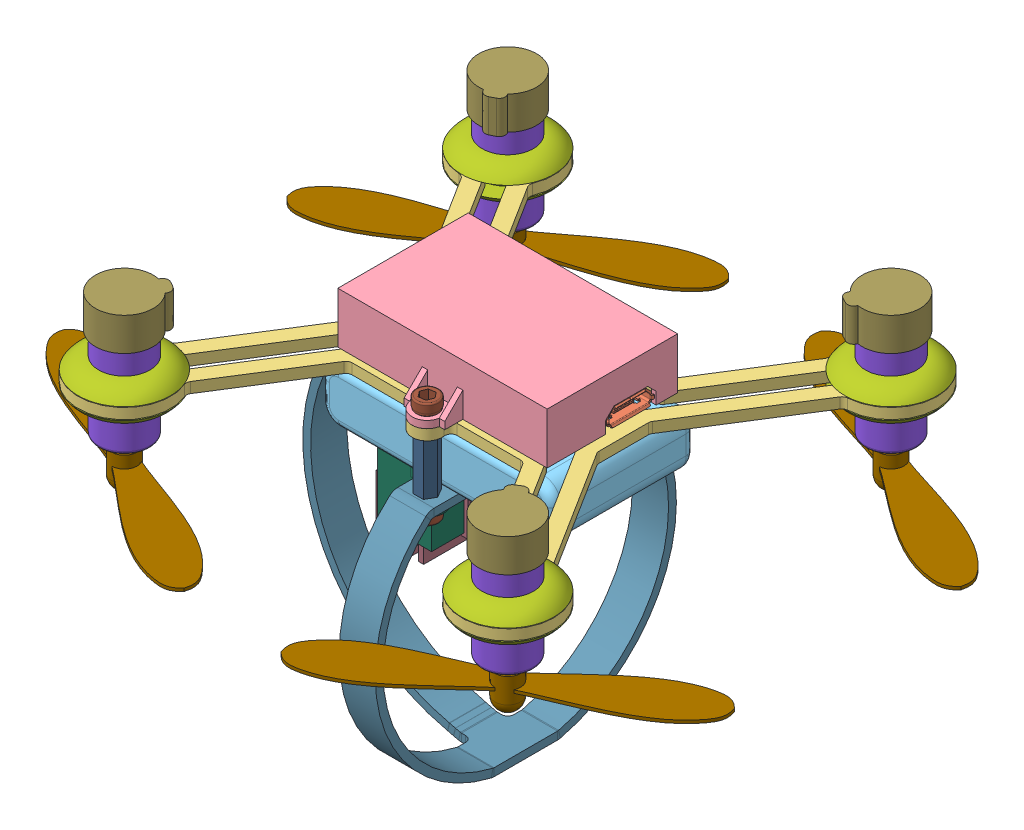
SolidWorks assembly quad, configuration Default. Lengths in mm.
Overall size (117.74 65.6 101.69).
43 component instances, 16 part files, 107 mates.
Components (placement in the parent):
- flight-controller-assembly-1: flight-controller-assembly [Default] at (0 0.58 0) x (-1 0 0) z (0 0 1) size (33.88 5.23 19.65)
  - flight-controller-pcb-1: flight-controller-pcb [Default] at origin size (32.75 4.13 19.65)
  - micro-usb-1: micro-usb [Default] at (-14.725 2.305 -3.075) x (0 0 1) z (-1 0 0) size (7.98 2.94 5.43)
- frame-top-1: frame-top [Default] at (0 -5.2 0) size (78.94 1.75 78.94)
- fc-cover-1: fc-cover [Default] at (0 -3.45 0) x (1 0 0) z (0 1 0) size (40.62 31.75 8.48)
- battery-1: battery [Default] at (0 -14.35 0) size (38.5 9.15 23.75)
- battery-connector-1: battery-connector [Default] at (-6.055 3.255 0) x (0 0 1) z (-1 0 0) size (7.97 2.72 14.82)
- grommet-1: grommet [Default] at (31.8198 -7.325 31.8198) x (-0.821055 0 0.570849) z (-0.570849 0 -0.821055) size (15.3 6 15.3)
- grommet-7: grommet [Default] at (31.8198 -7.325 -31.8198) x (-0.698764 0 0.715353) z (-0.715353 0 -0.698764) size (15.3 6 15.3)
- grommet-8: grommet [Default] at (-31.8198 -7.325 -31.8198) x (-0.528123 0 0.849168) z (-0.849168 0 -0.528123) size (15.3 6 15.3)
- grommet-9: grommet [Default] at (-31.8198 -7.325 31.8198) x (-0.314334 0 0.949312) z (-0.949312 0 -0.314334) size (15.3 6 15.3)
- motor-with-prop-7: motor-with-prop [Default] at (31.8198 7.3 31.8198) x (0.839896 0 -0.542748) z (-0.542748 0 -0.839896) size (54.45 27.97 12.44)
  - motor-1: motor [Default] at origin size (8.5 25.55 8.5)
  - prop-1: prop [Default] at (0 21.5 0) size (54.45 6.22 12.44)
  - prop-volume-1: prop-volume [Default] at (0 21.5 0) size (54.45 3 54.45) (hidden)
- motor-with-prop-8: motor-with-prop [Default] at (31.8198 7.3 -31.8198) x (-0.887739 0 -0.460347) z (-0.460347 0 0.887739) size (54.45 27.97 12.44)
  - motor-1: motor [Default] at origin size (8.5 25.55 8.5)
  - prop-1: prop [Default] at (0 21.5 0) size (54.45 6.22 12.44)
  - prop-volume-1: prop-volume [Default] at (0 21.5 0) size (54.45 3 54.45) (hidden)
- motor-with-prop-9: motor-with-prop [Default] at (-31.8198 7.3 -31.8198) x (-0.890455 0 0.455071) z (0.455071 0 0.890455) size (54.45 27.97 12.44)
  - motor-1: motor [Default] at origin size (8.5 25.55 8.5)
  - prop-1: prop [Default] at (0 21.5 0) size (54.45 6.22 12.44)
  - prop-volume-1: prop-volume [Default] at (0 21.5 0) size (54.45 3 54.45) (hidden)
- motor-with-prop-10: motor-with-prop [Default] at (-31.8198 7.3 31.8198) x (0.865039 0 0.501705) z (0.501705 0 -0.865039) size (54.45 27.97 12.44)
  - motor-1: motor [Default] at origin size (8.5 25.55 8.5)
  - prop-1: prop [Default] at (0 21.5 0) size (54.45 6.22 12.44)
  - prop-volume-1: prop-volume [Default] at (0 21.5 0) size (54.45 3 54.45) (hidden)
- standoff-1: standoff [Default] at (0 -14.2 -13.375) x (0.866025 0 0.5) z (-0.5 0 0.866025) size (3 9 3.46)
- m2-cap-hex-socket-1: m2-cap-hex-socket [5mm] at (0 -17.95 -13.375) size (3.8 6.95 3.8)
- m2-cap-hex-socket-2: m2-cap-hex-socket [5mm] at (-20.75 -17.95 0) x (0.982082 0 -0.188455) z (0.188455 0 0.982082) size (3.8 6.95 3.8)
- m2-cap-hex-socket-3: m2-cap-hex-socket [5mm] at (0 -17.95 13.375) x (-0.947196 0 0.320656) z (-0.320656 0 -0.947196) size (3.8 6.95 3.8)
- standoff-3: standoff [Default] at (0 -14.2 13.375) x (-0.866025 0 -0.5) z (0.5 0 -0.866025) size (3 9 3.46)
- standoff-4: standoff [Default] at (-20.75 -14.2 0) x (0.5 0 -0.866025) z (0.866025 0 0.5) size (3 9 3.46)
- m2-cap-hex-socket-10: m2-cap-hex-socket [5mm] at (0 -0.3 13.375) x (-0.92593 0 -0.377696) z (-0.377696 0 0.92593) size (3.8 6.95 3.8)
- m2-cap-hex-socket-11: m2-cap-hex-socket [5mm] at (-20.75 -0.3 0) x (-0.958189 0 -0.286136) z (-0.286136 0 0.958189) size (3.8 6.95 3.8)
- m2-cap-hex-socket-12: m2-cap-hex-socket [5mm] at (0 -0.3 -13.375) x (-0.990666 0 -0.136312) z (-0.136312 0 0.990666) size (3.8 6.95 3.8)
- motor-foot-1: motor-foot [Default] at (31.8198 2.3 31.8198) x (-0.542748 0 -0.839896) z (0.839896 0 -0.542748) size (10.57 5.5 9.6)
- motor-foot-2: motor-foot [Default] at (-31.8198 2.3 31.8198) x (0.501705 0 -0.865039) z (0.865039 0 0.501705) size (10.57 5.5 9.6)
- motor-foot-4: motor-foot [Default] at (-31.8198 2.3 -31.8198) x (0.455071 0 0.890455) z (-0.890455 0 0.455071) size (10.57 5.5 9.6)
- motor-foot-6: motor-foot [Default] at (31.8198 2.3 -31.8198) x (-0.460347 0 0.887739) z (-0.887739 0 -0.460347) size (10.57 5.5 9.6)
- camera-1: camera [Default] at (-10.25 -22.5 0) x (0 0 1) z (1 0 0) size (19.47 14.27 17.48)
- camera-protector-1: camera-protector [Default] at (3 -14.2 0) x (-1 0 0) z (0 0 1) size (34.02 43.6 50)
- camera-mount-1: camera-mount [Default] at (0 -15.5 0) x (0 0 1) z (1 0 0) size (30.75 10.5 25.5)
Mates (geometry in assembly coordinates):
- Width3: width aligned: plane of frame-top-1 through (-19.25 -3.45 -11.875) normal (-1 0 0); plane of frame-top-1 through (19.25 -3.45 -11.875) normal (1 0 0); plane of battery-1 through (-19.25 -5.2 -11.875) normal (-1 0 0); plane of battery-1 through (19.25 -5.2 -11.875) normal (1 0 0)
- Width4: width aligned: plane of battery-1 through (-19.25 -5.2 -11.875) normal (0 0 -1); plane of battery-1 through (-19.25 -5.2 11.875) normal (0 0 1); plane of frame-top-1 through (-19.25 -3.45 -11.875) normal (0 0 -1); plane of frame-top-1 through (-19.25 -3.45 11.875) normal (0 0 1)
- Concentric1: concentric aligned: cylinder of frame-top-1 through (31.8198 -3.45 31.8198) axis (0 -1 0) radius 5.125; cylinder of grommet-1 through (31.8198 -1.325 31.8198) axis (0 -1 0) radius 4
- Concentric2: concentric aligned: cylinder of frame-top-1 through (-31.8198 -3.45 31.8198) axis (0 -1 0) radius 5.125; cylinder of ? through (-31.8198 -1.325 31.8198) axis (0 -1 0) radius 4
- Width8: width: plane of ? through (-31.8198 -5.325 31.8198) normal (0 1 0); plane of ? through (-31.8198 -3.325 31.8198) normal (0 -1 0); plane of frame-top-1 through (0 -3.45 0) normal (0 1 0); plane of frame-top-1 through (0 -5.2 0) normal (0 -1 0)
- Width9: width: plane of ? through (-31.8198 -5.325 -31.8198) normal (0 1 0); plane of ? through (-31.8198 -3.325 -31.8198) normal (0 -1 0); plane of frame-top-1 through (0 -3.45 0) normal (0 1 0); plane of frame-top-1 through (0 -5.2 0) normal (0 -1 0)
- Concentric3: concentric aligned: cylinder of frame-top-1 through (-31.8198 -3.45 -31.8198) axis (0 -1 0) radius 5.125; cylinder of ? through (-31.8198 -1.325 -31.8198) axis (0 -1 0) radius 4
- Width10: width: plane of ? through (31.8198 -5.325 -31.8198) normal (0 1 0); plane of ? through (31.8198 -3.325 -31.8198) normal (0 -1 0); plane of frame-top-1 through (0 -3.45 0) normal (0 1 0); plane of frame-top-1 through (0 -5.2 0) normal (0 -1 0)
- Concentric4: concentric aligned: cylinder of frame-top-1 through (31.8198 -3.45 -31.8198) axis (0 -1 0) radius 5.125; cylinder of ? through (31.8198 -1.325 -31.8198) axis (0 -1 0) radius 4
- Distance1: distance = 10 mm aligned: plane of ? through (34.5 -15.2 28.5) normal (0 -1 0); plane of frame-top-1 through (0 -5.2 0) normal (0 -1 0)
- Concentric6: concentric aligned: cylinder of ? through (-34.5 -1.325 28.5) axis (0 -1 0) radius 4; cylinder of ? through (-34.5 36.8208 28.5) axis (0 -1 0) radius 4.25
- Distance2: distance = 10 mm aligned: plane of ? through (-34.5 -15.2 28.5) normal (0 -1 0); plane of frame-top-1 through (0 -5.2 0) normal (0 -1 0)
- Distance3: distance = 10 mm aligned: plane of ? through (-34.5 -15.2 -28.5) normal (0 -1 0); plane of frame-top-1 through (0 -5.2 0) normal (0 -1 0)
- Concentric7: concentric aligned: cylinder of ? through (-34.5 -1.325 -28.5) axis (0 -1 0) radius 4; cylinder of ? through (-34.5 36.8208 -28.5) axis (0 -1 0) radius 4.25
- Distance4: distance = 10 mm aligned: plane of ? through (34.5 -15.2 -28.5) normal (0 -1 0); plane of frame-top-1 through (0 -5.2 0) normal (0 -1 0)
- Concentric8: concentric aligned: cylinder of ? through (34.5 -1.325 -28.5) axis (0 -1 0) radius 4; cylinder of ? through (34.5 36.8208 -28.5) axis (0 -1 0) radius 4.25
- Concentric9: concentric anti-aligned: cylinder of ? through (34.5 -1.325 -28.5) axis (0 -1 0) radius 4; cylinder of ? through (34.5 -45.4121 -28.5) axis (0 1 0) radius 4.25
- Width12: width aligned: plane of frame-top-1 through (-19.25 -3.45 -11.875) normal (0 0 -1); plane of frame-top-1 through (-19.25 -3.45 11.875) normal (0 0 1); plane of ? through (-16.375 -3.45 9.825) normal (0 0 1); plane of ? through (-16.375 -3.45 -9.825) normal (0 0 -1)
- Width13: width aligned: plane of frame-top-1 through (-19.25 -3.45 -11.875) normal (-1 0 0); plane of frame-top-1 through (19.25 -3.45 -11.875) normal (1 0 0); plane of ? through (-16.375 -3.45 9.825) normal (-1 0 0); plane of ? through (16.375 -3.45 9.825) normal (1 0 0)
- InPlace1: in place: plane of ? through (0 -20.2 0) normal (0 -1 0); moOrthogonalPlaneRef_w of ?; line of ? through (-55 0 -20.2) axis (0 -1 0); unknown of ?
- Coincident9: coincident aligned: plane of ?; plane of assembly
- Coincident10: coincident aligned: unknown of ?
- Coincident11: coincident anti-aligned: line of ? through (-68.5518 0 -14.2) axis (0 -1 0)
- Concentric11: concentric anti-aligned: cylinder of ? through (31.8198 -1.325 -31.8198) axis (0 -1 0) radius 4; cylinder of ? through (31.8198 -45.7208 -31.8198) axis (0 1 0) radius 4.25
- Coincident13: coincident aligned: plane of motor-with-prop-7/motor-1 through (31.8198 -12.7 31.8198) normal (0 -1 0); plane of motor-with-prop-8/motor-1 through (31.8198 -12.7 -31.8198) normal (0 -1 0)
- Concentric12: concentric anti-aligned: cylinder of ? through (-31.8198 -1.325 -31.8198) axis (0 -1 0) radius 4; cylinder of ? through (-31.8198 -45.7208 -31.8198) axis (0 1 0) radius 4.25
- Coincident14: coincident aligned: plane of motor-with-prop-7/motor-1 through (31.8198 -12.7 31.8198) normal (0 -1 0); plane of motor-with-prop-9/motor-1 through (-31.8198 -12.7 -31.8198) normal (0 -1 0)
- Coincident15: coincident aligned: plane of motor-with-prop-7/motor-1 through (31.8198 -12.7 31.8198) normal (0 -1 0); plane of motor-with-prop-10/motor-1 through (-31.8198 -12.7 31.8198) normal (0 -1 0)
- Concentric13: concentric anti-aligned: cylinder of ? through (-31.8198 -1.325 31.8198) axis (0 -1 0) radius 4; cylinder of ? through (-31.8198 -45.7208 31.8198) axis (0 1 0) radius 4.25
- Coincident19: coincident anti-aligned: plane of ? through (0 -14.2 0) normal (0 1 0); plane of standoff-1 through (0 -14.2 -13.375) normal (0 -1 0)
- Parallel1: parallel aligned: plane of frame-top-1 through (-19.25 -3.45 -11.875) normal (0 0 -1); plane of standoff-1 through (0.866 -5.2 -14.875) normal (0 0 -1)
- Coincident21: coincident anti-aligned: plane of camera-mount-1 through (0 -16 0) normal (0 -1 0); plane of m2-cap-hex-socket-1 through (0 -16 -13.375) normal (0 1 0)
- Coincident22: coincident anti-aligned: plane of ? through (0 -3.45 0) normal (0 -1 0); plane of frame-top-1 through (0 -3.45 0) normal (0 1 0)
- Coincident23: coincident aligned: plane of ? through (0 -14.2 0) normal (0 1 0); plane of motor-with-prop-10/prop-volume-1 through (-31.8198 -14.2 31.8198) normal (0 1 0)
- Width16: width anti-aligned: plane of grommet-1 through (31.8198 -3.325 31.8198) normal (0 -1 0); plane of grommet-1 through (31.8198 -5.325 31.8198) normal (0 1 0); plane of frame-top-1 through (0 -3.45 0) normal (0 1 0); plane of frame-top-1 through (0 -5.2 0) normal (0 -1 0)
- Concentric17: concentric anti-aligned: cylinder of frame-top-1 through (31.8198 -3.45 -31.8198) axis (0 -1 0) radius 5.125; cylinder of motor-with-prop-8/motor-1 through (31.8198 -44.7208 -31.8198) axis (0 1 0) radius 4.25
- Concentric18: concentric anti-aligned: cylinder of frame-top-1 through (-31.8198 -3.45 -31.8198) axis (0 -1 0) radius 5.125; cylinder of motor-with-prop-9/motor-1 through (-31.8198 -44.7208 -31.8198) axis (0 1 0) radius 4.25
- Concentric19: concentric anti-aligned: cylinder of frame-top-1 through (-31.8198 -3.45 31.8198) axis (0 -1 0) radius 5.125; cylinder of motor-with-prop-10/motor-1 through (-31.8198 -44.7208 31.8198) axis (0 1 0) radius 4.25
- Concentric20: concentric anti-aligned: cylinder of frame-top-1 through (31.8198 -3.45 31.8198) axis (0 -1 0) radius 5.125; cylinder of motor-with-prop-7/motor-1 through (31.8198 -44.7208 31.8198) axis (0 1 0) radius 4.25
- Concentric21: concentric aligned: cylinder of frame-top-1 through (31.8198 -3.45 -31.8198) axis (0 -1 0) radius 5.125; cylinder of grommet-7 through (31.8198 -1.325 -31.8198) axis (0 -1 0) radius 4
- Width17: width anti-aligned: plane of grommet-7 through (31.8198 -3.325 -31.8198) normal (0 -1 0); plane of grommet-7 through (31.8198 -5.325 -31.8198) normal (0 1 0); plane of frame-top-1 through (0 -3.45 0) normal (0 1 0); plane of frame-top-1 through (0 -5.2 0) normal (0 -1 0)
- Width18: width anti-aligned: plane of grommet-8 through (-31.8198 -3.325 -31.8198) normal (0 -1 0); plane of grommet-8 through (-31.8198 -5.325 -31.8198) normal (0 1 0); plane of frame-top-1 through (0 -3.45 0) normal (0 1 0); plane of frame-top-1 through (0 -5.2 0) normal (0 -1 0)
- Concentric22: concentric aligned: cylinder of frame-top-1 through (-31.8198 -3.45 -31.8198) axis (0 -1 0) radius 5.125; cylinder of grommet-8 through (-31.8198 -1.325 -31.8198) axis (0 -1 0) radius 4
- Width19: width anti-aligned: plane of grommet-9 through (-31.8198 -3.325 31.8198) normal (0 -1 0); plane of grommet-9 through (-31.8198 -5.325 31.8198) normal (0 1 0); plane of frame-top-1 through (0 -3.45 0) normal (0 1 0); plane of frame-top-1 through (0 -5.2 0) normal (0 -1 0)
- Concentric23: concentric aligned: cylinder of frame-top-1 through (-31.8198 -3.45 31.8198) axis (0 -1 0) radius 5.125; cylinder of grommet-9 through (-31.8198 -1.325 31.8198) axis (0 -1 0) radius 4
- Coincident24: coincident anti-aligned: plane of camera-mount-1 through (0 -16 0) normal (0 -1 0); plane of m2-cap-hex-socket-2 through (-20.75 -16 0) normal (0 1 0)
- Coincident25: coincident anti-aligned: plane of camera-mount-1 through (0 -16 0) normal (0 -1 0); plane of m2-cap-hex-socket-3 through (0 -16 13.375) normal (0 1 0)
- Coincident26: coincident anti-aligned: plane of ? through (0 -16.3 0) normal (0 -1 0); plane of ? through (31.8198 -16.3 0) normal (0 1 0)
- Coincident32: coincident anti-aligned: plane of ? through (0 -15.2 0) normal (0 1 0); plane of ? through (31.8198 -15.2 0) normal (0 -1 0)
- Parallel2: parallel aligned: plane of frame-top-1 through (19.25 -3.45 -11.875) normal (1 0 0); plane of ? through (33.3198 -5.2 0.866) normal (1 0 0)
- Coincident33: coincident anti-aligned: plane of ? through (0 -14.2 0) normal (0 1 0); plane of standoff-3 through (0 -14.2 13.375) normal (0 -1 0)
- Parallel3: parallel aligned: plane of frame-top-1 through (-19.25 -3.45 11.875) normal (0 0 1); plane of standoff-3 through (-0.866 -5.2 14.875) normal (0 0 1)
- Coincident34: coincident anti-aligned: plane of ? through (0 -14.2 0) normal (0 1 0); plane of standoff-4 through (-20.75 -14.2 0) normal (0 -1 0)
- Parallel4: parallel aligned: plane of frame-top-1 through (-19.25 -3.45 -11.875) normal (-1 0 0); plane of standoff-4 through (-22.25 -5.2 -0.866) normal (-1 0 0)
- Coincident39: coincident anti-aligned: plane of frame-top-1 through (0 -3.45 0) normal (0 1 0); plane of ? through (31.8198 -3.45 0) normal (0 -1 0)
- Concentric24: concentric aligned: cylinder of m2-cap-hex-socket-3 through (0 -16 13.375) axis (0 -1 0) radius 1.9; cylinder of standoff-3 through (0 -5.2 13.375) axis (0 -1 0) radius 0.85
- Concentric25: concentric anti-aligned: cylinder of standoff-3 through (0 -5.2 13.375) axis (0 -1 0) radius 0.85; cylinder of m2-cap-hex-socket-10 through (0 -2.25 13.375) axis (0 1 0) radius 1.9
- Concentric26: concentric aligned: cylinder of frame-top-1 through (0 3.6211 13.375) axis (0 -1 0) radius 1; cylinder of standoff-3 through (0 -5.2 13.375) axis (0 -1 0) radius 0.85
- Concentric27: concentric aligned: cylinder of frame-top-1 through (-20.75 3.6211 0) axis (0 -1 0) radius 1; cylinder of standoff-4 through (-20.75 -5.2 0) axis (0 -1 0) radius 0.85
- Concentric28: concentric anti-aligned: cylinder of standoff-4 through (-20.75 -5.2 0) axis (0 -1 0) radius 0.85; cylinder of m2-cap-hex-socket-11 through (-20.75 -2.25 0) axis (0 1 0) radius 1.9
- Concentric29: concentric aligned: cylinder of m2-cap-hex-socket-2 through (-20.75 -16 0) axis (0 -1 0) radius 1.9; cylinder of standoff-4 through (-20.75 -5.2 0) axis (0 -1 0) radius 0.85
- Concentric30: concentric aligned: cylinder of standoff-1 through (0 -5.2 -13.375) axis (0 -1 0) radius 0.85; cylinder of m2-cap-hex-socket-1 through (0 -16 -13.375) axis (0 -1 0) radius 1.9
- Concentric31: concentric anti-aligned: cylinder of standoff-1 through (0 -5.2 -13.375) axis (0 -1 0) radius 0.85; cylinder of m2-cap-hex-socket-12 through (0 -2.25 -13.375) axis (0 1 0) radius 1.9
- Concentric32: concentric aligned: cylinder of frame-top-1 through (0 3.6211 -13.375) axis (0 -1 0) radius 1; cylinder of standoff-1 through (0 -5.2 -13.375) axis (0 -1 0) radius 0.85
- Coincident40: coincident anti-aligned: plane of frame-top-1 through (0 -5.2 0) normal (0 -1 0); plane of battery-1 through (0 -5.2 0) normal (0 1 0)
- InPlace2: in place: plane of frame-top-1 through (0 -3.45 0) normal (0 1 0); plane of fc-cover-1 through (0 -3.45 0) normal (0 1 0); plane of frame-top-1 through (0 -3.45 0) normal (0 1 0); plane of fc-cover-1 through (0 -3.45 0) normal (0 0 -1); plane of frame-top-1 through (0 -3.45 0) normal (0 1 0); line of fc-cover-1 through (-55 0 -3.45) axis (0 1 0); plane of frame-top-1 through (0 -3.45 0) normal (0 1 0); unknown of fc-cover-1
- Coincident42: coincident aligned: plane of frame-top-1; plane of fc-cover-1
- Coincident43: coincident aligned: moOrthogonalPlaneRef_w of frame-top-1 through (0 -3.45 0) normal (0 0 -1); plane of fc-cover-1 through (0 -3.45 0) normal (0 0 -1)
- Coincident44: coincident anti-aligned: moOrthogonalPlaneRef_w of frame-top-1 through (0 -3.45 0) normal (-1 0 0); plane of fc-cover-1
- Concentric33: concentric anti-aligned: cylinder of ? through (20.75 -47.2178 0) axis (0 1 0) radius 1; cylinder of ? through (20.75 -3.3 0) axis (0 -1 0) radius 1
- Coincident42: coincident anti-aligned: plane of ? through (0 -16.3 0) normal (0 -1 0); plane of ? through (20.75 -16.3 0) normal (0 1 0)
- Distance5: distance = 0.5 mm aligned: plane of fc-cover-1 through (-17.375 58.5902 0) normal (-1 0 0); plane of battery-connector-1 through (-16.875 3.255 0) normal (-1 0 0)
- Coincident46: coincident anti-aligned: plane of fc-cover-1 through (0 -2.25 0) normal (0 1 0); plane of m2-cap-hex-socket-10 through (0 -2.25 13.375) normal (0 -1 0)
- Coincident47: coincident anti-aligned: plane of fc-cover-1 through (0 -2.25 0) normal (0 1 0); plane of m2-cap-hex-socket-11 through (-20.75 -2.25 0) normal (0 -1 0)
- Coincident48: coincident anti-aligned: plane of fc-cover-1 through (0 -2.25 0) normal (0 1 0); plane of m2-cap-hex-socket-12 through (0 -2.25 -13.375) normal (0 -1 0)
- Concentric34: concentric anti-aligned: cylinder of motor-with-prop-7/motor-1 through (31.8198 -44.7208 31.8198) axis (0 1 0) radius 4.25; cylinder of motor-foot-1 through (31.8198 7.3 31.8198) axis (0 -1 0) radius 4.3
- Coincident49: coincident anti-aligned: plane of motor-with-prop-7/motor-1 through (31.8198 7.3 31.8198) normal (0 1 0); plane of motor-foot-1 through (31.8198 7.3 31.8198) normal (0 -1 0)
- Coincident50: coincident aligned: plane of motor-with-prop-7/motor-1; plane of motor-foot-1 through (31.8198 2.3 31.8198) normal (0.839896 0 -0.542748)
- Concentric35: concentric anti-aligned: cylinder of motor-with-prop-10/motor-1 through (-31.8198 -44.7208 31.8198) axis (0 1 0) radius 4.25; cylinder of motor-foot-2 through (-31.8198 7.3 31.8198) axis (0 -1 0) radius 4.3
- Coincident51: coincident anti-aligned: plane of motor-with-prop-10/motor-1 through (-31.8198 7.3 31.8198) normal (0 1 0); plane of motor-foot-2 through (-31.8198 7.3 31.8198) normal (0 -1 0)
- Coincident52: coincident aligned: plane of motor-with-prop-10/motor-1; plane of motor-foot-2 through (-31.8198 2.3 31.8198) normal (0.865039 0 0.501705)
- Concentric36: concentric anti-aligned: cylinder of motor-with-prop-9/motor-1 through (-31.8198 -44.7208 -31.8198) axis (0 1 0) radius 4.25; cylinder of motor-foot-4 through (-31.8198 7.3 -31.8198) axis (0 -1 0) radius 4.3
- Coincident53: coincident anti-aligned: plane of motor-with-prop-9/motor-1 through (-31.8198 7.3 -31.8198) normal (0 1 0); plane of motor-foot-4 through (-31.8198 7.3 -31.8198) normal (0 -1 0)
- Coincident54: coincident aligned: plane of motor-with-prop-9/motor-1; plane of motor-foot-4 through (-31.8198 2.3 -31.8198) normal (-0.890455 0 0.455071)
- Concentric37: concentric anti-aligned: cylinder of motor-with-prop-8/motor-1 through (31.8198 -44.7208 -31.8198) axis (0 1 0) radius 4.25; cylinder of motor-foot-6 through (31.8198 7.3 -31.8198) axis (0 -1 0) radius 4.3
- Coincident55: coincident anti-aligned: plane of motor-with-prop-8/motor-1 through (31.8198 7.3 -31.8198) normal (0 1 0); plane of motor-foot-6 through (31.8198 7.3 -31.8198) normal (0 -1 0)
- Coincident56: coincident aligned: plane of motor-with-prop-8/motor-1; plane of motor-foot-6 through (31.8198 2.3 -31.8198) normal (-0.887739 0 -0.460347)
- Distance6: distance = 0.5 mm anti-aligned: plane of flight-controller-assembly-1/micro-usb-1 through (12.375 -2.95 0.125) normal (0 -1 0); plane of frame-top-1 through (0 -3.45 0) normal (0 1 0)
- Width23: width aligned: plane of frame-top-1 through (-19.25 -3.45 -11.875) normal (0 0 -1); plane of frame-top-1 through (-19.25 -3.45 11.875) normal (0 0 1); plane of flight-controller-assembly-1/flight-controller-pcb-1 through (16.375 -0.5 -9.825) normal (0 0 -1); plane of flight-controller-assembly-1/flight-controller-pcb-1 through (16.375 -0.5 9.825) normal (0 0 1)
- Width24: width aligned: plane of frame-top-1 through (19.25 -3.45 -11.875) normal (1 0 0); plane of frame-top-1 through (-19.25 -3.45 -11.875) normal (-1 0 0); plane of flight-controller-assembly-1/flight-controller-pcb-1 through (16.375 -0.5 -9.825) normal (1 0 0); plane of flight-controller-assembly-1/flight-controller-pcb-1 through (-16.375 -0.5 -9.825) normal (-1 0 0)
- Width25: width aligned: plane of fc-cover-1 through (0 58.5902 10.825) normal (0 0 1); plane of fc-cover-1 through (0 58.5902 -10.825) normal (0 0 -1); plane of battery-connector-1 through (-16.875 4.53 -3.985) normal (0 0 -1); plane of battery-connector-1 through (-16.875 4.53 3.985) normal (0 0 1)
- Coincident58: coincident anti-aligned: plane of fc-cover-1 through (0 4.53 0) normal (0 -1 0); plane of battery-connector-1 through (-10.655 4.53 -2.3) normal (0 1 0)
- Coincident59: coincident anti-aligned: plane of ? through (0 -15.5 0) normal (0 -1 0); plane of camera-protector-1 through (-3.2 -15.5 -54.5043) normal (0 1 0)
- Concentric38: concentric anti-aligned: cylinder of ? through (0 -47.1545 -13.375) axis (0 1 0) radius 1; cylinder of camera-protector-1 through (0 -15.499 -13.375) axis (0 -1 0) radius 1
- Concentric39: concentric anti-aligned: cylinder of ? through (-20.75 -47.1545 0) axis (0 1 0) radius 1; cylinder of camera-protector-1 through (-20.75 -15.499 0) axis (0 -1 0) radius 1
- Coincident60: coincident anti-aligned: plane of camera-protector-1 through (-3 -15.5 16) normal (0 -1 0); plane of camera-mount-1 through (0 -15.5 0) normal (0 1 0)
- Concentric40: concentric aligned: cylinder of ? through (0 -47.1545 13.375) axis (0 1 0) radius 1; cylinder of camera-mount-1 through (0 -17.3 13.375) axis (0 1 0) radius 1.25
- Concentric41: concentric aligned: cylinder of ? through (0 -47.1545 -13.375) axis (0 1 0) radius 1; cylinder of camera-mount-1 through (0 -17.3 -13.375) axis (0 1 0) radius 1.25
- Coincident61: coincident anti-aligned: plane of camera-1 through (-4.57 -16 -9.385) normal (0 1 0); plane of camera-mount-1 through (0 -16 0) normal (0 -1 0)
- Coincident62: coincident anti-aligned: plane of camera-1 through (-11.25 -22.5 0) normal (-1 0 0); plane of camera-mount-1 through (-11.25 -26 9.4) normal (1 0 0)
- Width29: width aligned: plane of camera-mount-1 through (0 -16 9.9) normal (0 0 1); plane of camera-mount-1 through (0 -16 -9.9) normal (0 0 -1); plane of camera-1 through (-9.4 -29 9.385) normal (0 0 1); plane of camera-1 through (-9.4 -29 -9.385) normal (0 0 -1)
- Concentric42: concentric aligned: cylinder of standoff-1 through (0 -5.2 -13.375) axis (0 -1 0) radius 0.85; cylinder of camera-protector-1 through (0 -14.199 -13.375) axis (0 -1 0) radius 1
- Concentric43: concentric aligned: cylinder of standoff-3 through (0 -5.2 13.375) axis (0 -1 0) radius 0.85; cylinder of camera-protector-1 through (0 -14.199 13.375) axis (0 -1 0) radius 1
- Coincident63: coincident anti-aligned: plane of standoff-3 through (0 -14.2 13.375) normal (0 -1 0); plane of camera-protector-1 through (-3 -14.2 -16) normal (0 1 0)
- Coincident64: coincident anti-aligned: plane of standoff-1 through (0 -14.2 -13.375) normal (0 -1 0); plane of camera-protector-1 through (-3 -14.2 -16) normal (0 1 0)
- Coincident65: coincident anti-aligned: plane of standoff-4 through (-20.75 -14.2 0) normal (0 -1 0); plane of camera-protector-1 through (-3.2 -14.2 -54.5043) normal (0 1 0)
- Coincident66: coincident anti-aligned: plane of frame-top-1 through (0 -5.2 0) normal (0 -1 0); plane of standoff-4 through (-20.75 -5.2 0) normal (0 1 0)
